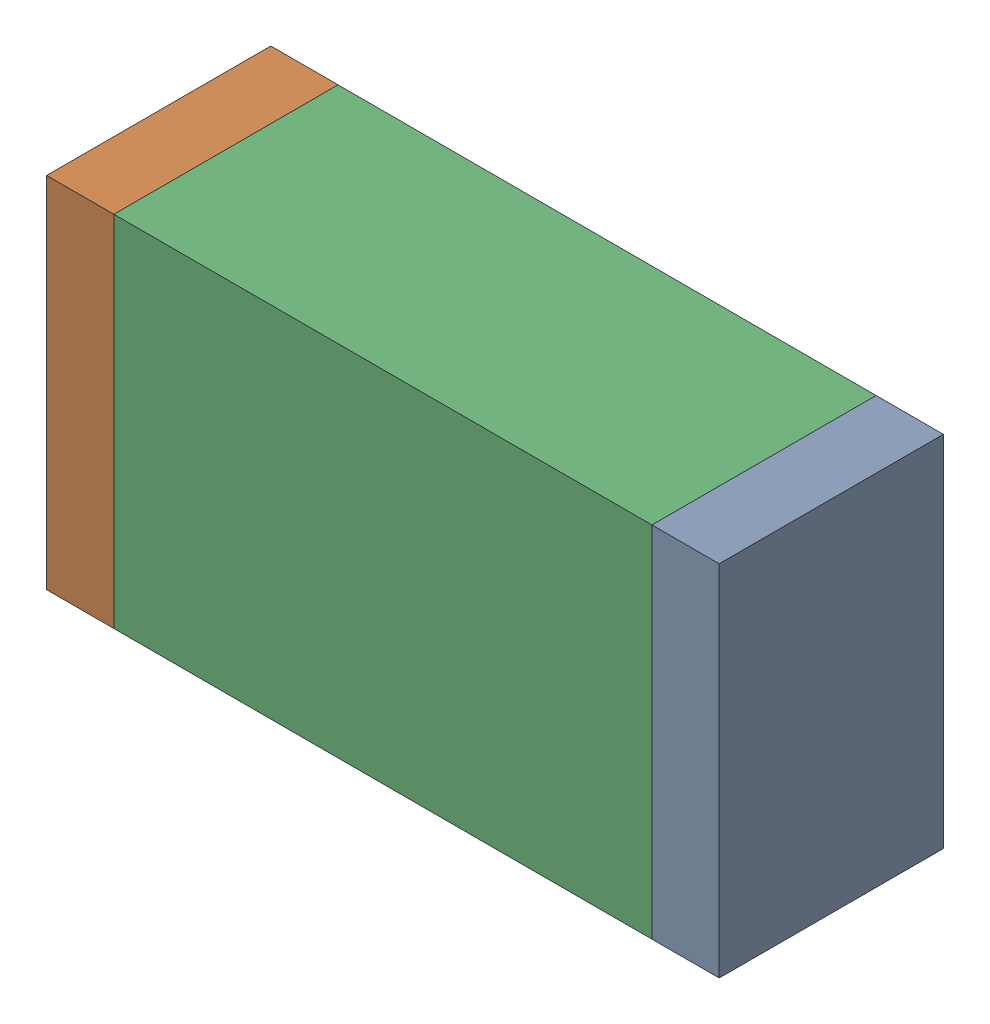
SolidWorks assembly D3, configuration Default. Lengths in mm.
Overall size (1.5 0.8 0.5).
6 component instances, 2 part files, 0 mates.
Components (placement in the parent):
- 836752496-1: 836752496 [Default] at (127.725 10.7 0) size (0.15 0.8 0.5)
  - Extruded_2-1: Extruded_2 [Default] at origin size (0.15 0.8 0.5)
- 836752496-2: 836752496 [Default] at (126.375 10.7 0) size (0.15 0.8 0.5)
  - Extruded_2-1: Extruded_2 [Default] at origin size (0.15 0.8 0.5)
- 836752368-1: 836752368 [Default] at (127.05 10.7 0) size (1.2 0.8 0.5)
  - Extruded-1: Extruded [Default] at origin size (1.2 0.8 0.5)
